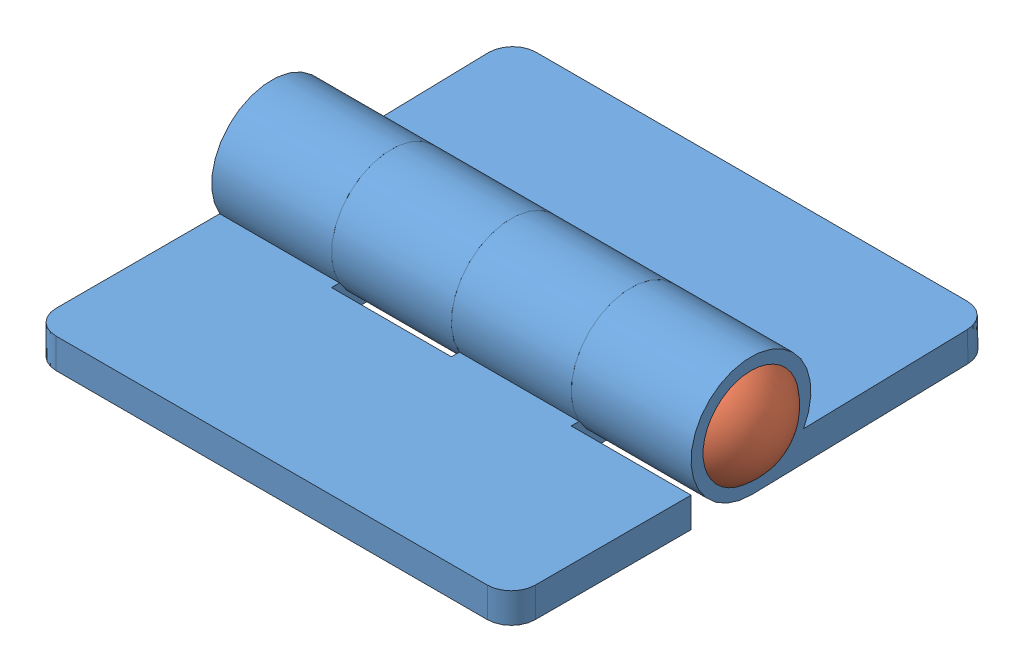
SolidWorks assembly Hinge Assembly, configuration Default. Lengths in mm.
Overall size (55.88 13.47 50.95).
3 component instances, 2 part files, 3 mates.
Components (placement in the parent):
- Hinge Piece-1: Hinge Piece [Default] at (8.1249 17.6047 53.2265) size (50.8 12.7 31.75)
- Hinge Piece-2: Hinge Piece [Default] at (8.1249 18.0034 20.4703) x (-1 0 0) z (0 0.02434 -0.999704) size (50.8 12.7 31.75)
- Hinge Pin-1: Hinge Pin [Default] at (-17.2751 23.9547 36.9233) x (0 0 -1) z (1 0 0) size (10.16 10.16 55.88)
Mates (geometry in assembly coordinates):
- Hinge1: hinge aligned: cylinder of Hinge Piece-2 through (-4.5751 23.9547 36.9233) axis (1 0 0) radius 3.175; cylinder of Hinge Piece-1 through (-4.5751 23.9547 36.9233) axis (-1 0 0) radius 3.175; plane of Hinge Piece-2 through (-17.2751 21.3989 11.4535) normal (-1 0 0); plane of Hinge Piece-1 through (-17.2751 20.7797 62.3233) normal (-1 0 0)
- Coincident1: coincident anti-aligned: plane of Hinge Piece-2 through (33.5249 21.3989 11.4535) normal (1 0 0); plane of Hinge Pin-1 through (33.5249 23.9547 36.9233) normal (-1 0 0)
- Concentric1: concentric aligned: cylinder of Hinge Piece-1 through (-4.5751 23.9547 36.9233) axis (-1 0 0) radius 3.175; cylinder of Hinge Pin-1 through (33.5249 23.9547 36.9233) axis (-1 0 0) radius 3.175
